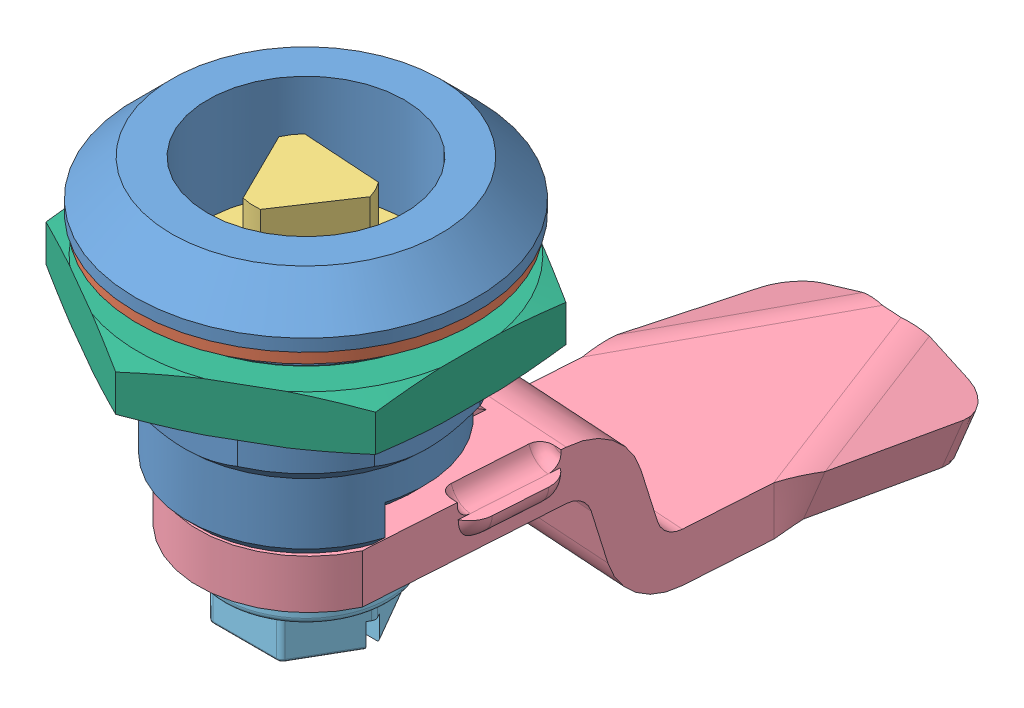
SolidWorks assembly AssemblageVERROU316L, configuration Défaut. Lengths in mm.
Overall size (28 37.77 61.63).
6 component instances, 6 part files, 11 mates.
Components (placement in the parent):
- CO02960130PCL-1: CO02960130PCL [Défaut] at (-4.9037 7.8695 0) size (28 22 28)
- JOINTVERROU-IP65-1: JOINTVERROU-IP65 [Défaut] at (-4.9037 6.8695 0) x (1 0 0) z (0 1 0) size (27.5 27.5 1)
- RO02411250CPL-1: RO02411250CPL [Défaut] at (-4.9037 3.4695 0) x (0 1 0) z (-0.064039 0 0.997947) size (25.3 16 16)
- CA02405480PCcame28-1: CA02405480PCcame28 [Défaut] at (-4.7975 -14.1305 -0.0934) x (0.064039 0 -0.997947) z (0.997947 0 0.064039) size (54.43 17.77 19.1)
- VISVERROUM6-1: VISVERROUM6 [Défaut] at (-4.9037 -20.1305 0) x (1 0 0) z (0 -1 0) size (13.5 13.5 13.31)
- ECROUVEROU-1: ECROUVEROU [Défaut] at (-4.9037 0.8695 0) x (1 0 0) z (0 1 0) size (27 31.18 4)
Mates (geometry in assembly coordinates):
- Coaxiale1: concentric anti-aligned: cylinder of CO02960130PCL-1 through (-4.9037 13.7823 0) axis (0 1 0) radius 10.85; cylinder of JOINTVERROU-IP65-1 through (-4.9037 7.8695 0) axis (0 -1 0) radius 11
- Coïncidente1: coincident anti-aligned: plane of CO02960130PCL-1 through (5.9463 7.8695 0) normal (0 -1 0); plane of JOINTVERROU-IP65-1 through (-4.9037 7.8695 0) normal (0 1 0)
- Coïncidente3: coincident anti-aligned: plane of CO02960130PCL-1 through (3.1463 -3.5305 0) normal (0 1 0); plane of RO02411250CPL-1 through (-11.1907 -3.5305 -0.4034) normal (0 -1 0)
- Coaxiale3: concentric aligned: cylinder of CO02960130PCL-1 through (-4.9037 13.7823 0) axis (0 1 0) radius 5; cylinder of RO02411250CPL-1 through (-4.9037 3.4695 0) axis (0 1 0) radius 4.95
- Coïncidente4: coincident anti-aligned: plane of CO02960130PCL-1 through (3.7963 -10.1305 0) normal (0 -1 0); plane of CA02405480PCcame28-1 through (3.0089 -10.1305 9.4261) normal (0 1 0)
- Coïncidente5: coincident anti-aligned: plane of RO02411250CPL-1 through (-2.2499 -14.8305 4.1785) normal (-0.064039 0 0.997947); plane of CA02405480PCcame28-1 through (3.3227 -14.1305 4.5361) normal (0.064039 0 -0.997947)
- Coïncidente6: coincident anti-aligned: plane of RO02411250CPL-1 through (-9.0822 -14.8305 2.6538) normal (-0.997947 0 -0.064039); plane of CA02405480PCcame28-1 through (-9.4654 -14.1305 8.6256) normal (0.997947 0 0.064039)
- Coïncidente7: coincident: plane of RO02411250CPL-1 through (-4.9037 -14.8305 0) normal (0 -1 0); point of VISVERROUM6-1
- Coaxiale4: concentric aligned: cylinder of RO02411250CPL-1 through (-4.9037 -14.8305 0) axis (0 -1 0) radius 2.75; cylinder of VISVERROUM6-1 through (-4.9037 -6.8305 0) axis (0 -1 0) radius 3
- Coaxiale5: concentric anti-aligned: cylinder of CO02960130PCL-1 through (-4.9037 13.7823 0) axis (0 1 0) radius 10.85; cylinder of ECROUVEROU-1 through (-4.9037 4.8695 0) axis (0 -1 0) radius 10.25
- Distance1: distance = 2 mm anti-aligned: plane of ECROUVEROU-1 through (8.5963 4.8695 -7.7942) normal (0 1 0); plane of JOINTVERROU-IP65-1 through (-4.9037 6.8695 0) normal (0 -1 0)
